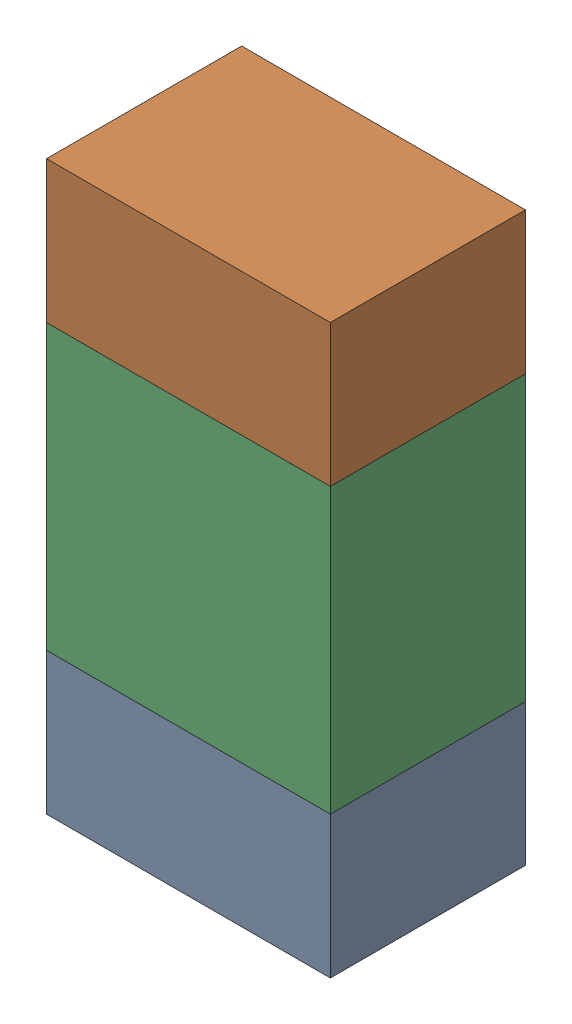
SolidWorks assembly R36, configuration ﾃﾞﾌｫﾙﾄ. Lengths in mm.
Overall size (0.8 1.6 0.55).
6 component instances, 2 part files, 0 mates.
Components (placement in the parent):
- 689261784-1: 689261784 [ﾃﾞﾌｫﾙﾄ] at (30.4999 69.1501 0) size (0.8 0.4 0.55)
  - Extruded_34-1: Extruded_34 [ﾃﾞﾌｫﾙﾄ] at origin size (0.8 0.4 0.55)
- 689261784-2: 689261784 [ﾃﾞﾌｫﾙﾄ] at (30.4999 70.3501 0) size (0.8 0.4 0.55)
  - Extruded_34-1: Extruded_34 [ﾃﾞﾌｫﾙﾄ] at origin size (0.8 0.4 0.55)
- 689261648-1: 689261648 [ﾃﾞﾌｫﾙﾄ] at (30.4999 69.75 0) size (0.8 0.8 0.55)
  - Extruded_33-1: Extruded_33 [ﾃﾞﾌｫﾙﾄ] at origin size (0.8 0.8 0.55)
